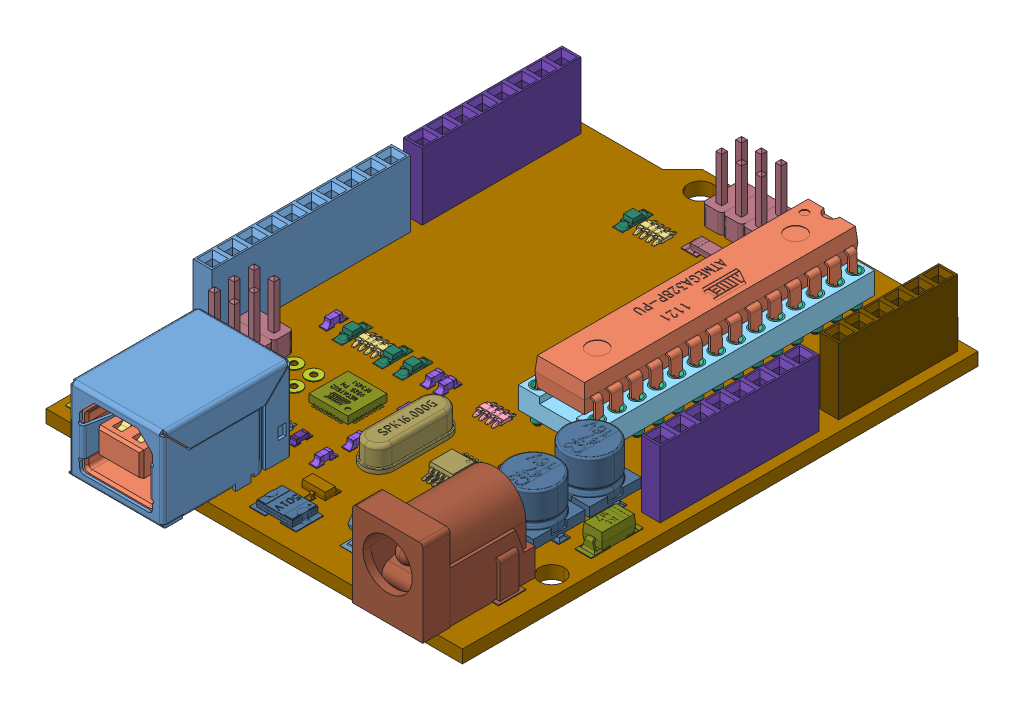
SolidWorks assembly arduino uno, configuration Default. Lengths in mm.
Overall size (53.34 15.26 74.97).
88 component instances, 35 part files, 0 mates.
Components (placement in the parent):
- arduino uno.step-1: arduino uno.step [Default] at origin size (53.34 15.26 74.97)
  - USB type b.step-1: USB type b.step [Default] at (-38.02 0.43 6.35) size (13.91 15.21 16.55)
    - USB SHELL.step-1: USB SHELL.step [Default] at origin size (13.91 15.21 16.55)
    - USB core.step-1: USB core.step [Default] at origin size (11.3 10.68 15.75)
    - usb top contact.step-1: usb top contact.step [Default] at (1.25 6.09 -0.38) size (1 9.67 13.76)
    - usb btm contact.step-1: usb btm contact.step [Default] at (1.25 4.41 -0.38) size (1 6.84 11.76)
    - usb btm contact.step-2: usb btm contact.step [Default] at (-1.25 4.41 -0.38) size (1 6.84 11.76)
    - usb top contact.step-2: usb top contact.step [Default] at (-1.25 6.09 -0.38) size (1 9.67 13.76)
  - dip28.step-1: dip28.step [Default] at (-16.383 1.5 -46.355) x (0 0 -1) z (1 0 0) size (35.48 7.37 10.1)
    - dip28-0.step-1: dip28-0.step [Default] at origin size (35.48 2.8 10.1)
    - dip socket pin.step-1: dip socket pin.step [Default] at (16.51 2.8 -3.81) size (1.7 7.37 1.7)
    - dip socket pin.step-2: dip socket pin.step [Default] at (16.51 2.8 3.81) size (1.7 7.37 1.7)
    - dip socket pin.step-3: dip socket pin.step [Default] at (13.97 2.8 -3.81) size (1.7 7.37 1.7)
    - dip socket pin.step-4: dip socket pin.step [Default] at (13.97 2.8 3.81) size (1.7 7.37 1.7)
    - dip socket pin.step-5: dip socket pin.step [Default] at (11.43 2.8 -3.81) size (1.7 7.37 1.7)
    - dip socket pin.step-6: dip socket pin.step [Default] at (11.43 2.8 3.81) size (1.7 7.37 1.7)
    - dip socket pin.step-7: dip socket pin.step [Default] at (8.89 2.8 -3.81) size (1.7 7.37 1.7)
    - dip socket pin.step-8: dip socket pin.step [Default] at (8.89 2.8 3.81) size (1.7 7.37 1.7)
    - dip socket pin.step-9: dip socket pin.step [Default] at (6.35 2.8 -3.81) size (1.7 7.37 1.7)
    - dip socket pin.step-10: dip socket pin.step [Default] at (6.35 2.8 3.81) size (1.7 7.37 1.7)
    - dip socket pin.step-11: dip socket pin.step [Default] at (3.81 2.8 -3.81) size (1.7 7.37 1.7)
    - dip socket pin.step-12: dip socket pin.step [Default] at (3.81 2.8 3.81) size (1.7 7.37 1.7)
    - dip socket pin.step-13: dip socket pin.step [Default] at (1.27 2.8 -3.81) size (1.7 7.37 1.7)
    - dip socket pin.step-14: dip socket pin.step [Default] at (1.27 2.8 3.81) size (1.7 7.37 1.7)
    - dip socket pin.step-15: dip socket pin.step [Default] at (-1.27 2.8 -3.81) size (1.7 7.37 1.7)
    - dip socket pin.step-16: dip socket pin.step [Default] at (-1.27 2.8 3.81) size (1.7 7.37 1.7)
    - dip socket pin.step-17: dip socket pin.step [Default] at (-3.81 2.8 -3.81) size (1.7 7.37 1.7)
    - dip socket pin.step-18: dip socket pin.step [Default] at (-3.81 2.8 3.81) size (1.7 7.37 1.7)
    - dip socket pin.step-19: dip socket pin.step [Default] at (-6.35 2.8 -3.81) size (1.7 7.37 1.7)
    - dip socket pin.step-20: dip socket pin.step [Default] at (-6.35 2.8 3.81) size (1.7 7.37 1.7)
    - dip socket pin.step-21: dip socket pin.step [Default] at (-8.89 2.8 -3.81) size (1.7 7.37 1.7)
    - dip socket pin.step-22: dip socket pin.step [Default] at (-8.89 2.8 3.81) size (1.7 7.37 1.7)
    - dip socket pin.step-23: dip socket pin.step [Default] at (-11.43 2.8 -3.81) size (1.7 7.37 1.7)
    - dip socket pin.step-24: dip socket pin.step [Default] at (-11.43 2.8 3.81) size (1.7 7.37 1.7)
    - dip socket pin.step-25: dip socket pin.step [Default] at (-13.97 2.8 -3.81) size (1.7 7.37 1.7)
    - dip socket pin.step-26: dip socket pin.step [Default] at (-13.97 2.8 3.81) size (1.7 7.37 1.7)
    - dip socket pin.step-27: dip socket pin.step [Default] at (-16.51 2.8 -3.81) size (1.7 7.37 1.7)
    - dip socket pin.step-28: dip socket pin.step [Default] at (-16.51 2.8 3.81) size (1.7 7.37 1.7)
  - RESET BUTTON.step-1: RESET BUTTON.step [Default] at (-49.403 0 -6.35) size (6.2 3.1 9.6)
    - RESET CORE.step-1: RESET CORE.step [Default] at (0 0.1 0) x (-1 0 0) z (0 0 -1) size (6.2 3.1 9.6)
    - RESET.step-1: RESET.step [Default] at (0 0.1 0) x (0 0 1) z (-1 0 0) size (7.3 2 6.2)
  - unoboard blue.step-1: unoboard blue.step [Default] at origin size (53.34 1.65 68.58)
  - 47uf CAP Dcase.step-1: 47uf CAP Dcase.step [Default] at (-9.4141 0 -18.4991) x (0 0 -1) z (1 0 0) size (6.6 5.81 8)
  - power jack.step-1: power jack.step [Default] at (-7.675 0 1.905) size (11.2 15.2 15.9)
  - 47uf CAP Dcase.step-2: 47uf CAP Dcase.step [Default] at (-9.4141 0 -25.7132) x (0 0 -1) z (1 0 0) size (6.6 5.81 8)
  - crystal.step-1: crystal.step [Default] at (-26.162 0 -18.923) x (1 0 0) z (0 0 -1) size (4 5 11)
  - 2pin_header__02.step-1: 2pin_header__02.step [Default] at (-46.23 0 -15.75) size (5 11.75 2.54)
  - nano - reg.step-1: nano - reg.step [Default] at (-17.399 0 -7.747) size (6.5 1.69 8.3)
  - led.step-1: led.step [Default] at (-34.29 0 -27.94) x (0 0 1) z (-1 0 0) size (4 0.85 1.47)
  - 2pin_header__02.step-2: 2pin_header__02.step [Default] at (-30.43 0 -64.91) x (0 0 1) z (-1 0 0) size (5 11.75 2.54)
  - 2pin_header__02.step-3: 2pin_header__02.step [Default] at (-27.89 0 -64.91) x (0 0 1) z (-1 0 0) size (5 11.75 2.54)
  - 2pin_header__02.step-4: 2pin_header__02.step [Default] at (-25.35 0 -64.91) x (0 0 1) z (-1 0 0) size (5 11.75 2.54)
  - 2pin_header__02.step-5: 2pin_header__02.step [Default] at (-46.23 0 -18.29) size (5 11.75 2.54)
  - 2pin_header__02.step-6: 2pin_header__02.step [Default] at (-46.23 0 -20.83) size (5 11.75 2.54)
  - atmega16u2.step-1: atmega16u2.step [Default] at (-34.671 0.06 -20) x (1 0 0) z (0 0 -1) size (5.5 1.01 5.5)
  - led.step-2: led.step [Default] at (-36.83 0 -27.94) x (0 0 1) z (-1 0 0) size (4 0.85 1.47)
  - led.step-3: led.step [Default] at (-42.037 0 -27.94) x (0 0 1) z (-1 0 0) size (4 0.85 1.47)
  - led.step-4: led.step [Default] at (-36.576 0 -58.42) x (0 0 1) z (-1 0 0) size (4 0.85 1.47)
  - 8 PORT HEADER.step-1: 8 PORT HEADER.step [Default] at (-50.8 0 -45.72) x (0 0 -1) z (1 0 0) size (20.32 10.51 2.41)
  - 8 PORT HEADER.step-2: 8 PORT HEADER.step [Default] at (-2.54 0 -27.94) x (0 0 -1) z (1 0 0) size (20.32 10.51 2.41)
  - 6 PORT HEADER.step-1: 6 PORT HEADER.step [Default] at (-2.54 0 -50.8) x (0 0 -1) z (1 0 0) size (15.24 10.51 2.41)
  - 10 PORT HEADER.step-1: 10 PORT HEADER.step [Default] at (-50.8 0 -18.796) x (0 0 -1) z (1 0 0) size (25.4 10.51 2.41)
  - ATMEL328P.step-1: ATMEL328P.step [Default] at (-16.383 4.3 -46.355) x (0 0 -1) z (1 0 0) size (35 7.27 7.87)
  - 102 RESISTOR PACK.step-1: 102 RESISTOR PACK.step [Default] at (-33.782 0 -58.42) size (3.2 0.46 3)
  - 102 RESISTOR PACK.step-2: 102 RESISTOR PACK.step [Default] at (-39.37 0 -27.94) size (3.2 0.46 3)
  - 103 RESISTOR PACK.step-1: 103 RESISTOR PACK.step [Default] at (-23.876 0 -27.94) size (3.2 0.46 3)
  - 220 RESISTOR PACK.step-1: 220 RESISTOR PACK.step [Default] at (-36.83 0 -12.827) size (3.2 0.46 3)
  - 16mhz crystal - measured.step-1: 16mhz crystal - measured.step [Default] at (-24.892 0 -41.275) x (0 0 -1) z (1 0 0) size (3.4 0.8 2)
  - PADS001.step-1: PADS001.step [Default] at (-39.878 0.1 -18.288) x (-1 0 0) z (0 0 1) size (4.54 0.1 4.54)
  - 603 cap on pad.step-1: 603 cap on pad.step [Default] at (-44.45 0 -27.94) x (0 0 -1) z (1 0 0) size (2.76 0.9 1.03)
  - ssot3.step-1: ssot3.step [Default] at (-26.5 0 -8.128) x (-1 0 0) z (0 0 -1) size (3 1.13 3.09)
  - mf-msmf050-2.step-1: mf-msmf050-2.step [Default] at (-26.5 0 -4.064) size (5.86 1.02 3.72)
  - 603 cap on pad.step-2: 603 cap on pad.step [Default] at (-29.845 0 -27.94) x (0 0 -1) z (1 0 0) size (2.76 0.9 1.03)
  - 603 cap on pad.step-3: 603 cap on pad.step [Default] at (-31.496 0 -27.94) x (0 0 -1) z (1 0 0) size (2.76 0.9 1.03)
  - lmv358.step-1: lmv358.step [Default] at (-15.24 0 -21.971) x (0 0 -1) z (1 0 0) size (3.7 1.4 2.9)
  - 603 cap on pad.step-4: 603 cap on pad.step [Default] at (-15.24 0 -18.415) size (2.76 0.9 1.03)
  - 603 cap on pad.step-5: 603 cap on pad.step [Default] at (-29.845 0 -12.065) x (0 0 1) z (-1 0 0) size (2.76 0.9 1.03)
  - 603 cap on pad.step-6: 603 cap on pad.step [Default] at (-29.591 0 -22.352) x (0 0 1) z (-1 0 0) size (2.76 0.9 1.03)
  - 603 cap on pad.step-7: 603 cap on pad.step [Default] at (-29.591 0 -16.002) x (0 0 1) z (-1 0 0) size (2.76 0.9 1.03)
  - 603 cap on pad.step-8: 603 cap on pad.step [Default] at (-41.91 0 -12.7) x (0 0 1) z (-1 0 0) size (2.76 0.9 1.03)
  - lp2985dgkr.step-1: lp2985dgkr.step [Default] at (-20.32 0 -19.05) x (0 0 -1) z (1 0 0) size (5.85 1.1 3)
  - cd1206 diode.step-1: cd1206 diode.step [Default] at (-27.94 0 -59.436) x (0 0 -1) z (1 0 0) size (2.01 0.96 5)
  - cd1206 diode.step-2: cd1206 diode.step [Default] at (-46.228 0 -13.081) x (0 0 1) z (-1 0 0) size (2.01 0.96 5)
  - 603 resistor.step-1: 603 resistor.step [Default] at (-29.591 0 -19.05) x (0 0 1) z (-1 0 0) size (2.36 0.61 1.02)
  - blm21.step-1: blm21.step [Default] at (-45.085 0 -7.62) x (0 0 -1) z (1 0 0) size (2.78 0.95 1.32)
  - m7 diode.step-1: m7 diode.step [Default] at (-2.794 0 -21.59) x (0 0 -1) z (1 0 0) size (6.66 2.35 2.5)
  - MLC0603.step-1: MLC0603.step [Default] at (-33.655 0 -12.827) x (0 0 -1) z (1 0 0) size (2.36 0.6 1.02)
  - MLC0603.step-2: MLC0603.step [Default] at (-39.37 0 -12.827) x (0 0 -1) z (1 0 0) size (2.36 0.6 1.02)
